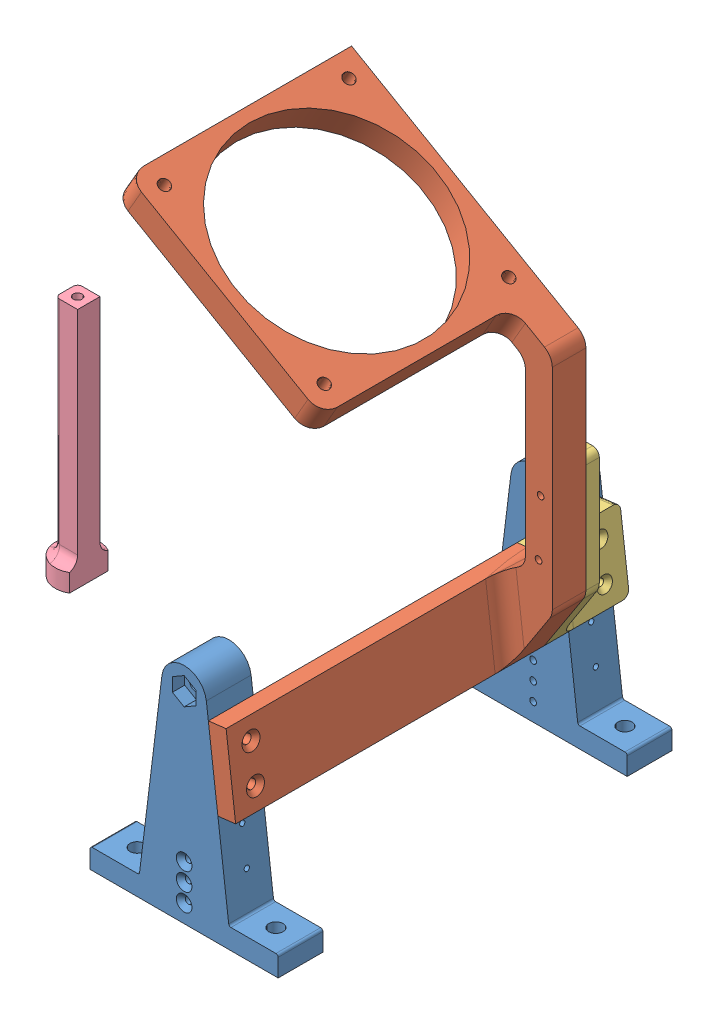
SolidWorks assembly zostava_halogenka, configuration Default. Lengths in mm.
Overall size (210.58 274.38 176).
5 component instances, 4 part files, 14 mates.
Components (placement in the parent):
- noha-1: noha [Default] at (-61.2219 61.1953 7.9062) size (84.04 100 20)
- noha-2: noha [Default] at (-61.2219 61.1953 -128.0938) x (-1 0 0) z (0 0 -1) size (84.04 100 20)
- Part1-1: Part1 [Default] at (-61.2219 61.1953 27.9062) size (110.73 190 138.01)
- Part2-1: Part2 [Default] at (-61.2219 61.1953 -110.0938) x (-1 0 0) z (0 0 -1) size (30.75 83.13 38)
- podpora_pred-1: podpora_pred [Default] at (-219.7852 -28.8047 -83.0414) x (0 0 -1) z (0 1 0) size (20 15 108)
Mates (geometry in assembly coordinates):
- Parallel1: parallel aligned: plane of noha-1 through (-19.2012 61.1953 27.9062) normal (1 0 0); plane of noha-2 through (-19.2012 61.1953 -148.0938) normal (1 0 0)
- Coincident3: coincident aligned: plane of noha-1 through (-61.2219 -28.8047 27.9062) normal (0 -1 0); plane of noha-2 through (-61.2219 -28.8047 -148.0938) normal (0 -1 0)
- Coincident4: coincident aligned: plane of noha-1 through (-19.2012 61.1953 27.9062) normal (1 0 0); plane of noha-2 through (-19.2012 61.1953 -148.0938) normal (1 0 0)
- Distance2: distance = 136 mm anti-aligned: plane of noha-1 through (-61.2219 61.1953 7.9062) normal (0 0 -1); plane of noha-2 through (-61.2219 61.1953 -128.0938) normal (0 0 1)
- InPlace1: in place: plane of noha-1 through (-61.2219 61.1953 27.9062) normal (0 0 1); plane of ? through (0 0 27.9062) normal (0 0 1); moOrthogonalPlaneRef_w of noha-1 through (-61.2219 61.1953 27.9062) normal (0 0 1); plane of ? through (0 0 27.9062) normal (0 1 0); plane of noha-1 through (-61.2219 61.1953 27.9062) normal (0 0 1); plane of ? through (0 0 27.9062) normal (1 0 0); plane of noha-1 through (-61.2219 61.1953 27.9062) normal (0 0 1); unknown of Part1-1
- Coincident7: coincident aligned: plane of noha-1; plane of Part1-1
- Coincident8: coincident aligned: moOrthogonalPlaneRef_w of noha-1 through (-61.2219 61.1953 27.9062) normal (0 1 0); plane of Part1-1 through (-61.2219 61.1953 27.9062) normal (0 1 0)
- Coincident9: coincident anti-aligned: moOrthogonalPlaneRef_w of noha-1 through (-61.2219 61.1953 27.9062) normal (-1 0 0); plane of Part1-1 through (-61.2219 61.1953 27.9062) normal (1 0 0)
- InPlace2: in place: plane of Part1-1 through (-61.2219 61.1953 -110.0938) normal (0 0 -1); plane of ? through (0 0 -110.0938) normal (0 0 -1); plane of Part1-1 through (-61.2219 61.1953 -110.0938) normal (0 0 -1); unknown of ?; plane of Part1-1 through (-61.2219 61.1953 -110.0938) normal (0 0 -1); plane of ? through (0 0 -110.0938) normal (-1 0 0); plane of Part1-1 through (-61.2219 61.1953 -110.0938) normal (0 0 -1); unknown of Part2-1
- Coincident5: coincident aligned: plane of Part1-1; plane of Part2-1
- Coincident6: coincident aligned: moOrthogonalPlaneRef_w of Part1-1 through (-61.2219 61.1953 -110.0938) normal (0 1 0); plane of Part2-1 through (-61.2219 61.1953 -110.0938) normal (0 1 0)
- Coincident7: coincident anti-aligned: moOrthogonalPlaneRef_w of Part1-1 through (-61.2219 61.1953 -110.0938) normal (1 0 0); plane of Part2-1 through (-61.2219 61.1953 -110.0938) normal (-1 0 0)
- Coincident5: coincident aligned: plane of noha-2 through (-61.2219 -28.8047 -148.0938) normal (0 -1 0); plane of podpora_pred-1 through (-219.7852 -28.8047 -83.0414) normal (0 -1 0)
- Parallel2: parallel aligned: plane of noha-2 through (-61.2219 61.1953 -148.0938) normal (0 0 -1); plane of podpora_pred-1 through (-214.7852 79.1953 -88.0414) normal (0 0 -1)
